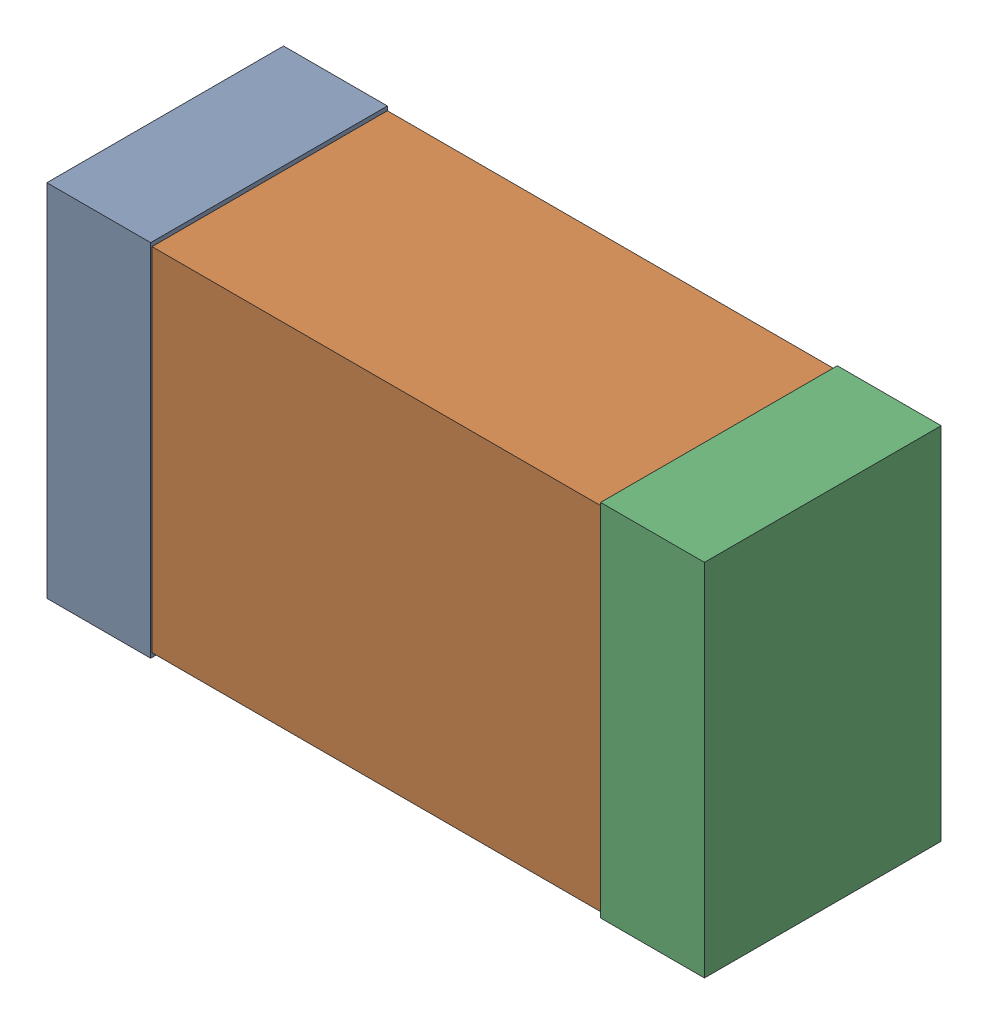
SolidWorks assembly C14_Motor_10Kanaloa_v2.0.0_Motor, configuration Default. Lengths in mm.
Overall size (2.38 1.3 0.85).
6 component instances, 2 part files, 0 mates.
Components (placement in the parent):
- 352877648-1: 352877648 [Default] at (76.74 166.624 0) size (0.38 1.3 0.85)
  - Extruded_14-1: Extruded_14 [Default] at origin size (0.38 1.3 0.85)
- 352877392-1: 352877392 [Default] at (77.74 166.624 0) size (2.2 1.27 0.85)
  - Extruded_15-1: Extruded_15 [Default] at origin size (2.2 1.27 0.85)
- 352877648-2: 352877648 [Default] at (78.74 166.624 0) size (0.38 1.3 0.85)
  - Extruded_14-1: Extruded_14 [Default] at origin size (0.38 1.3 0.85)
